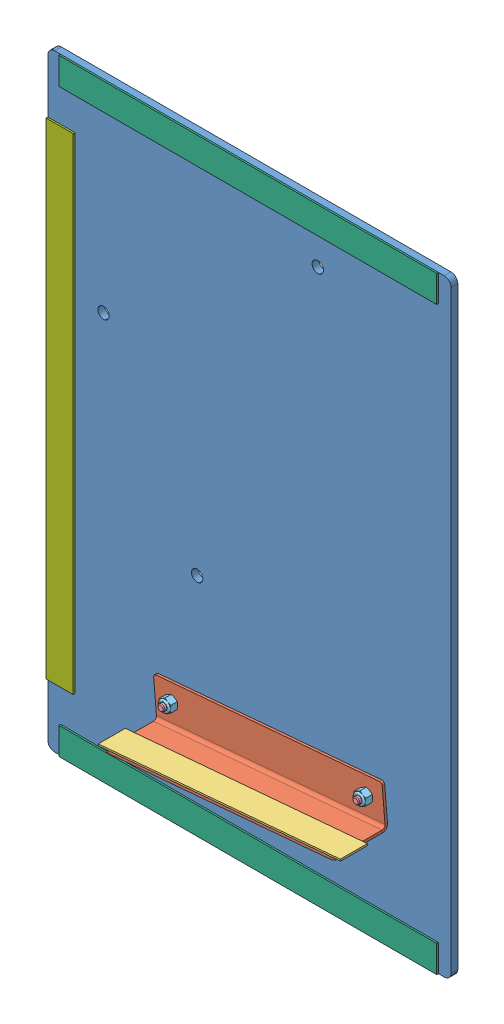
SolidWorks assembly GE-22326, configuration Default. Lengths in mm.
Overall size (379.41 571.5 61.12).
11 component instances, 7 part files, 20 mates.
Components (placement in the parent):
- GE-22324-1: GE-22324 [Default] at origin size (379.41 571.5 6.35)
- GE-22337-1: GE-22337 [Default] at (212.4724 84.1347 6.35) x (-0.996195 -0.087156 0) z (0 0 -1) size (228.6 38.1 50.8)
  - GE-22325-1: GE-22325 [Default] at (-107.95 0 -2.3048) x (0 0 -1) z (1 0 0) size (50.8 38.1 215.9)
  - Hook_1_9-1: Hook_1_9 [Default] at (-114.3 2.3048 -25.4) size (228.6 1.59 25.4)
- hex_.25_20_0.75-3: hex_.25_20_0.75 [Default] at (302.26 114.3 7.5406) x (0 0 1) z (-1 0 0) size (23.02 12.83 11.11)
- nylock_.25_20-1: nylock_.25_20 [Default] at (118.8107 98.2503 8.6548) x (1 0 0) z (0 -1 0) size (11.11 7.94 12.83)
- nylock_.25_20-2: nylock_.25_20 [Default] at (302.26 114.3 8.6548) x (1 0 0) z (0 -1 0) size (11.11 7.94 12.83)
- hex_.25_20_0.75-2: hex_.25_20_0.75 [Default] at (118.8107 98.2503 7.5406) x (0 0 1) z (-1 0 0) size (23.02 12.83 11.11)
- Loop_1_14-3: Loop_1_14 [Default] at (11.9062 25.4 7.9375) x (1 0 0) z (0 1 0) size (355.6 1.59 25.4)
- Loop_1_14-2: Loop_1_14 [Default] at (11.9062 571.5 7.9375) x (1 0 0) z (0 1 0) size (355.6 1.59 25.4)
- Loop_1_18-2: Loop_1_18 [Default] at (0 57.15 7.9375) x (0 1 0) z (-1 0 0) size (457.2 1.59 25.4)
Mates (geometry in assembly coordinates):
- Concentric1: concentric aligned: cylinder of GE-22324-1 through (302.26 114.3 0) axis (0 0 -1) radius 3.3782; cylinder of GE-22337-1/GE-22325-1 through (302.26 114.3 6.35) axis (0 0 -1) radius 3.3782
- Concentric2: concentric aligned: cylinder of GE-22324-1 through (118.8107 98.2503 0) axis (0 0 -1) radius 3.3782; cylinder of GE-22337-1/GE-22325-1 through (118.8107 98.2503 6.35) axis (0 0 -1) radius 3.3782
- Coincident1: coincident anti-aligned: plane of GE-22324-1 through (0 0 6.35) normal (0 0 1); plane of GE-22337-1/GE-22325-1 through (320.0116 93.5432 6.35) normal (0 0 -1)
- Concentric3: concentric anti-aligned: cylinder of GE-22324-1 through (302.26 114.3 0) axis (0 0 -1) radius 3.3782; cylinder of hex_.25_20_0.75-3 through (302.26 114.3 0) axis (0 0 1) radius 3.175
- Coincident7: coincident anti-aligned: plane of GE-22324-1 through (0 0 0) normal (0 0 -1); plane of hex_.25_20_0.75-3 through (296.7038 117.5079 0) normal (0 0 1)
- Concentric4: concentric aligned: cylinder of hex_.25_20_0.75-3 through (302.26 114.3 0) axis (0 0 1) radius 3.175; cylinder of nylock_.25_20-2 through (302.26 114.3 8.6548) axis (0 0 1) radius 3.175
- Coincident8: coincident anti-aligned: plane of GE-22337-1/GE-22325-1 through (320.0116 93.5432 8.6548) normal (0 0 1); plane of nylock_.25_20-2 through (302.26 114.3 8.6548) normal (0 0 -1)
- Concentric5: concentric anti-aligned: cylinder of GE-22324-1 through (118.8107 98.2503 0) axis (0 0 -1) radius 3.3782; cylinder of hex_.25_20_0.75-2 through (118.8107 98.2503 0) axis (0 0 1) radius 3.175
- Coincident9: coincident anti-aligned: plane of GE-22324-1 through (0 0 0) normal (0 0 -1); plane of hex_.25_20_0.75-2 through (113.2545 101.4582 0) normal (0 0 1)
- Concentric6: concentric aligned: cylinder of nylock_.25_20-1 through (118.8107 98.2503 8.6548) axis (0 0 1) radius 3.175; cylinder of hex_.25_20_0.75-2 through (118.8107 98.2503 0) axis (0 0 1) radius 3.175
- Coincident11: coincident anti-aligned: plane of GE-22337-1/GE-22325-1 through (320.0116 93.5432 8.6548) normal (0 0 1); plane of nylock_.25_20-1 through (118.8107 98.2503 8.6548) normal (0 0 -1)
- Coincident12: coincident anti-aligned: plane of GE-22324-1 through (0 0 6.35) normal (0 0 1); plane of Loop_1_14-3 through (11.9062 25.4 6.35) normal (0 0 -1)
- Coincident22: coincident aligned: plane of GE-22324-1 through (379.4125 571.5 6.35) normal (0 1 0); plane of Loop_1_14-2 through (11.9062 571.5 6.35) normal (0 1 0)
- Coincident16: coincident anti-aligned: plane of GE-22324-1 through (0 0 6.35) normal (0 0 1); plane of Loop_1_14-2 through (11.9062 571.5 6.35) normal (0 0 -1)
- Coincident17: coincident aligned: plane of GE-22324-1 through (0 0 6.35) normal (0 -1 0); plane of Loop_1_14-3 through (11.9062 0 6.35) normal (0 -1 0)
- Coincident23: coincident anti-aligned: plane of GE-22324-1 through (0 0 6.35) normal (0 0 1); plane of Loop_1_18-2 through (0 57.15 6.35) normal (0 0 -1)
- Coincident24: coincident aligned: plane of GE-22324-1 through (0 0 6.35) normal (-1 0 0); plane of Loop_1_18-2 through (0 57.15 6.35) normal (-1 0 0)
- Width2: width anti-aligned: plane of GE-22324-1 through (0 0 6.35) normal (-1 0 0); plane of Loop_1_14-3 through (379.4125 571.5 6.35) normal (1 0 0); plane of GE-22324-1 through (367.5062 25.4 6.35) normal (1 0 0); plane of Loop_1_14-3 through (11.9062 25.4 6.35) normal (-1 0 0)
- Width3: width aligned: plane of GE-22324-1 through (0 0 6.35) normal (0 -1 0); plane of Loop_1_18-2 through (379.4125 571.5 6.35) normal (0 1 0); plane of GE-22324-1 through (0 57.15 6.35) normal (0 -1 0); plane of Loop_1_18-2 through (0 514.35 6.35) normal (0 1 0)
- Coincident25: coincident aligned: plane of Loop_1_14-3 through (11.9062 25.4 6.35) normal (-1 0 0); plane of Loop_1_14-2 through (11.9062 571.5 6.35) normal (-1 0 0)
